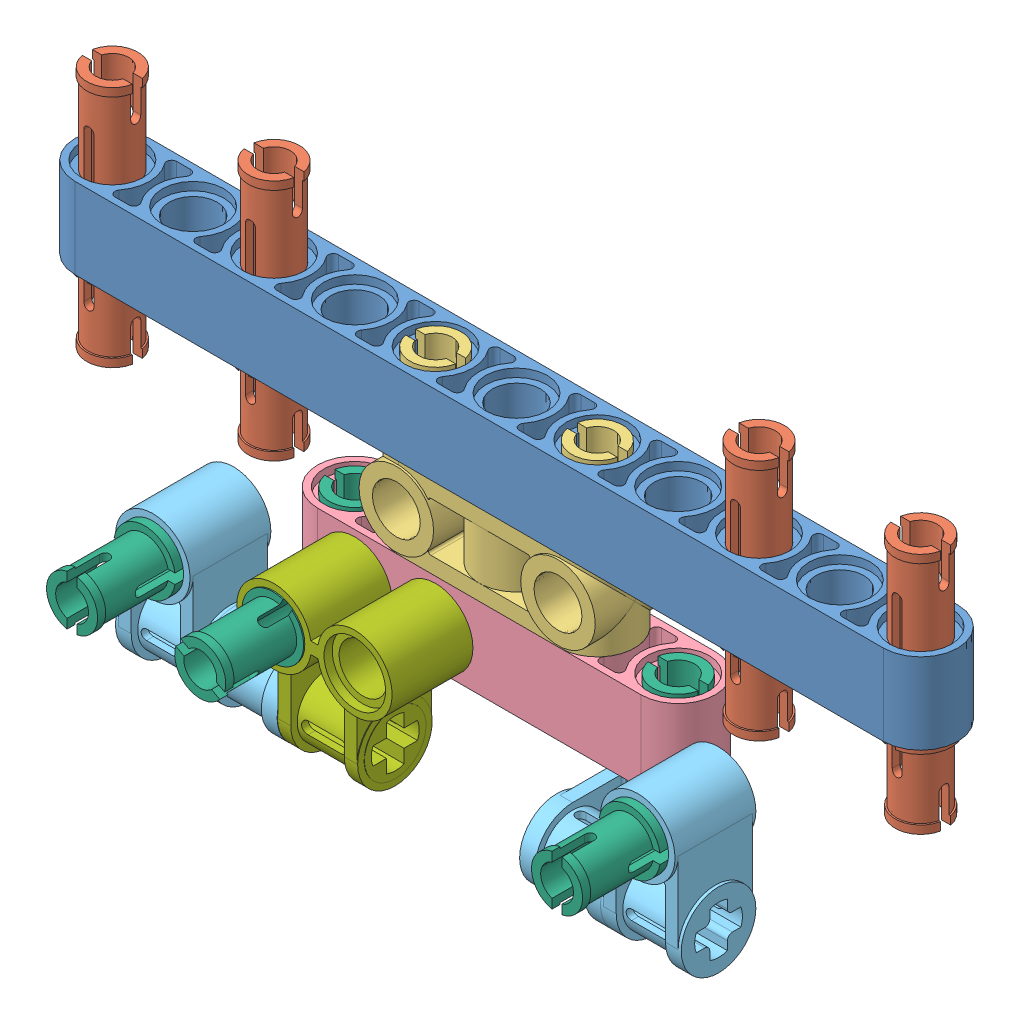
SolidWorks assembly NXT Mount RH, configuration Default. Lengths in mm.
Overall size (88.09 40.29 24.07).
17 component instances, 7 part files, 42 mates.
Components (placement in the parent):
- beam_11-1: beam_11 [Default] at (-40.325 -4.0325 0) size (88.09 8.06 7.44)
- conn_3-1: conn_3 [Default] at (40.325 -0.0325 0) x (1 0 0) z (0 0 -1) size (6.15 24.2 6.07)
- conn_3-2: conn_3 [Default] at (24.195 -0.0325 0) x (1 0 0) z (0 0 -1) size (6.15 24.2 6.07)
- conn_3-3: conn_3 [Default] at (-24.195 -0.0325 0) x (1 0 0) z (0 0 -1) size (6.15 24.2 6.07)
- conn_3-4: conn_3 [Default] at (-40.325 -0.0325 0) x (1 0 0) z (0 0 -1) size (6.15 24.2 6.07)
- conn_3w-1: conn_3w [Default] at (0 -8.065 3.72) x (0 1 0) z (-1 0 0) size (24.2 7.85 23.57)
- beam_5-1: beam_5 [Default] at (16.13 -20.1625 0) x (-1 0 0) z (0 0 -1) size (39.7 8.06 7.44)
- crossblock_2-1: crossblock_2 [Default] at (-24.195 -20.1625 11.785) x (0 -1 0) z (1 0 0) size (15.5 8.06 8.06)
- crossblock_2-2: crossblock_2 [Default] at (16.13 -27.915 4.0325) x (0 0 1) z (-1 0 0) size (15.5 8.06 8.06)
- crossblock_2-3: crossblock_2 [Default] at (24.195 -20.1625 11.785) x (0 -1 0) z (1 0 0) size (15.5 8.06 8.06)
- crossblock_2-4: crossblock_2 [Default] at (-16.13 -27.915 4.0325) x (0 0 1) z (-1 0 0) size (15.5 8.06 8.06)
- conn-1: conn [Default] at (-16.13 -20.1625 0) x (-1 0 0) z (0 0 1) size (6.15 16.1 6.07)
- conn-2: conn [Default] at (16.13 -20.1625 0) x (1 0 0) z (0 0 -1) size (6.15 16.1 6.07)
- conn-3: conn [Default] at (-24.195 -16.13 12.0975) x (0 -1 0) z (-1 0 0) size (6.15 16.1 6.07)
- conn-4: conn [Default] at (24.195 -16.13 12.0975) x (0 1 0) z (-1 0 0) size (6.15 16.1 6.07)
- crossblock-1: crossblock [Default] at (-8.065 -16.13 8.065) x (1 0 0) z (0 1 0) size (15.5 8.06 15.51)
- conn-5: conn [Default] at (-12.0975 -16.13 11.4069) x (-0.875693 0.482869 0) z (-0.482869 -0.875693 0) size (6.15 16.1 6.07)
Mates (geometry in assembly coordinates):
- Concentric52: concentric anti-aligned: circle of beam_11-1; cylinder of conn_3w-1 through (8.065 3.2175 0) axis (0 -1 0) radius 2.39
- Concentric53: concentric anti-aligned: cylinder of beam_11-1 through (-8.065 -3.2175 0) axis (0 1 0) radius 2.39; cylinder of conn_3w-1 through (-8.065 3.2175 0) axis (0 -1 0) radius 2.39
- Coincident52: coincident anti-aligned: plane of beam_11-1 through (-45.8068 -4.0325 3.8688) normal (0 -1 0); plane of conn_3w-1 through (-12.2603 -4.0325 3.8688) normal (0 1 0)
- Coincident136: coincident anti-aligned: circle of beam_11-1; circle of conn_3-4
- Coincident138: coincident anti-aligned: circle of beam_11-1; circle of conn_3-3
- Coincident139: coincident anti-aligned: circle of beam_11-1; circle of conn_3-2
- Coincident140: coincident anti-aligned: circle of beam_11-1; circle of conn_3-1
- Parallel62: parallel anti-aligned: plane of beam_11-1 through (-40.325 -4.0325 0) normal (0 0 1); plane of conn_3-1 through (40.325 -0.0325 0) normal (0 0 -1)
- Parallel63: parallel anti-aligned: plane of beam_11-1 through (-40.325 -4.0325 0) normal (0 0 1); plane of conn_3-2 through (24.195 -0.0325 0) normal (0 0 -1)
- Parallel64: parallel anti-aligned: plane of beam_11-1 through (-40.325 -4.0325 0) normal (0 0 1); plane of conn_3-3 through (-24.195 -0.0325 0) normal (0 0 -1)
- Parallel65: parallel anti-aligned: plane of beam_11-1 through (-40.325 -4.0325 0) normal (0 0 1); plane of conn_3-4 through (-40.325 -0.0325 0) normal (0 0 -1)
- Concentric58: concentric anti-aligned: cylinder of conn_3w-1 through (8.065 -12.9125 0) axis (0 -1 0) radius 2.39; cylinder of beam_5-1 through (8.065 -19.3475 0) axis (0 1 0) radius 2.39
- Concentric59: concentric anti-aligned: cylinder of conn_3w-1 through (-8.065 -12.9125 0) axis (0 -1 0) radius 2.39; cylinder of beam_5-1 through (-8.065 -19.3475 0) axis (0 1 0) radius 2.39
- Coincident55: coincident anti-aligned: plane of conn_3w-1 through (12.2603 -12.0975 3.8688) normal (0 -1 0); plane of beam_5-1 through (20.6501 -12.0975 -3.8688) normal (0 1 0)
- Parallel10: parallel aligned: plane of conn_3w-1 through (-12.2564 -11.9338 3.925) normal (0 0 1); plane of crossblock_2-1 through (-20.3223 -12.2612 12.0975) normal (0 0 1)
- Parallel11: parallel aligned: plane of conn_3w-1 through (-12.2564 -11.9338 3.925) normal (0 0 1); plane of crossblock_2-3 through (28.0677 -12.2612 12.0975) normal (0 0 1)
- Parallel16: parallel aligned: plane of conn_3w-1 through (-12.2564 -11.9338 3.925) normal (0 0 1); plane of crossblock-1 through (-16.1313 -12.2603 12.0975) normal (0 0 1)
- Concentric60: concentric aligned: cylinder of crossblock_2-4 through (-16.13 -27.4125 0) axis (0 1 0) radius 2.39; cylinder of beam_5-1 through (-16.13 -19.3475 0) axis (0 1 0) radius 2.39
- Coincident59: coincident anti-aligned: plane of beam_5-1 through (20.6501 -20.1625 -3.8688) normal (0 -1 0); plane of crossblock_2-4 through (-20.0027 -20.1625 -3.8688) normal (0 1 0)
- Coincident60: coincident aligned: circle of beam_5-1; cylinder of crossblock_2-2 through (16.13 -27.4125 0) axis (0 1 0) radius 2.39
- Coincident62: coincident anti-aligned: plane of beam_5-1 through (20.6501 -20.1625 -3.8688) normal (0 -1 0); plane of crossblock_2-2 through (12.2573 -20.1625 -3.8688) normal (0 1 0)
- Coincident164: coincident anti-aligned: circle of beam_5-1; circle of conn-1
- Coincident165: coincident anti-aligned: circle of beam_5-1; circle of conn-2
- Concentric65: concentric anti-aligned: circle of crossblock_2-1; circle of crossblock_2-4
- Coincident65: coincident anti-aligned: plane of crossblock_2-1 through (-20.1625 -20.3262 11.9377) normal (1 0 0); plane of crossblock_2-4 through (-20.1625 -28.0677 4.1962) normal (-1 0 0)
- Coincident158: coincident anti-aligned: circle of crossblock_2-1; circle of conn-3
- Parallel7: parallel aligned: plane of crossblock_2-2 through (12.41 -28.0638 -0.1613) normal (-1 0 0); plane of crossblock_2-4 through (-19.85 -28.0638 -0.1613) normal (-1 0 0)
- Concentric66: concentric aligned: circle of crossblock_2-3; circle of crossblock_2-2
- Coincident69: coincident anti-aligned: plane of crossblock_2-2 through (20.1625 -28.0677 4.1962) normal (1 0 0); plane of crossblock_2-3 through (20.1625 -20.3262 11.9377) normal (-1 0 0)
- Concentric68: concentric anti-aligned: cylinder of crossblock_2-2 through (16.13 -27.4125 0) axis (0 1 0) radius 2.39; cylinder of conn-2 through (16.13 -12.9275 0) axis (0 -1 0) radius 2.39
- Coincident159: coincident aligned: circle of crossblock_2-3; circle of conn-4
- Concentric80: concentric anti-aligned: circle of crossblock-1; circle of crossblock_2-4
- Coincident80: coincident anti-aligned: plane of crossblock_2-4 through (-12.0975 -28.0677 4.1962) normal (1 0 0); plane of crossblock-1 through (-12.0975 -20.997 11.267) normal (-1 0 0)
- Concentric81: concentric aligned: cylinder of crossblock-1 through (-12.0975 -16.13 11.2825) axis (0 0 -1) radius 2.39; cylinder of conn-5 through (-12.0975 -16.13 10.5919) axis (0 0 -1) radius 2.39
- Lock12: lock: unknown of ?; unknown of ?
- Concentric82: concentric: cylinder of beam_11-1 through (0 -3.2175 0) axis (0 1 0) radius 2.39; point of assembly
- Coincident167: coincident aligned: plane of beam_11-1 through (-40.325 0 0) normal (0 1 0); plane of assembly
- Parallel66: parallel aligned: plane of beam_11-1 through (-40.325 -4.0325 0) normal (0 0 1); plane of assembly
- Parallel68: parallel anti-aligned: plane of assembly; plane of conn-2 through (16.13 -20.1625 0) normal (0 0 -1)
- Parallel69: parallel aligned: plane of assembly; plane of conn-1 through (-16.13 -20.1625 0) normal (0 0 1)
- Parallel70: parallel anti-aligned: plane of assembly; plane of conn-4 through (24.195 -16.13 12.0975) normal (-1 0 0)
- Parallel71: parallel anti-aligned: plane of assembly; plane of conn-3 through (-24.195 -16.13 12.0975) normal (-1 0 0)
